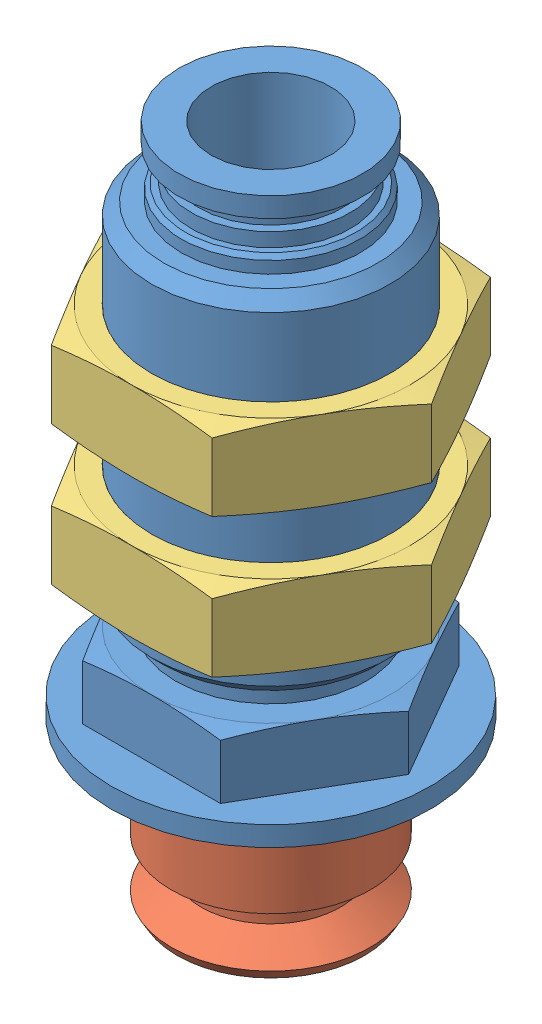
SolidWorks assembly 0059_004_MVPKN10, configuration Default. Lengths in mm.
Overall size (16.17 34 16).
4 component instances, 3 part files, 0 mates.
Components (placement in the parent):
- 0059_Z_MVPKN10_1_1-1: 0059_Z_MVPKN10_1_1 [Default] at origin size (16 26 16)
- 0059_Z_VPNT10-1: 0059_Z_VPNT10 [Default] at origin size (10 8 10)
- 0059_Z_MVPKN10_NUT_NUT-1: 0059_Z_MVPKN10_NUT_NUT [Default] at (0 3 0) size (16.17 4 14)
- 0059_Z_MVPKN10_NUT_NUT-2: 0059_Z_MVPKN10_NUT_NUT [Default] at (0 -4 0) size (16.17 4 14)
